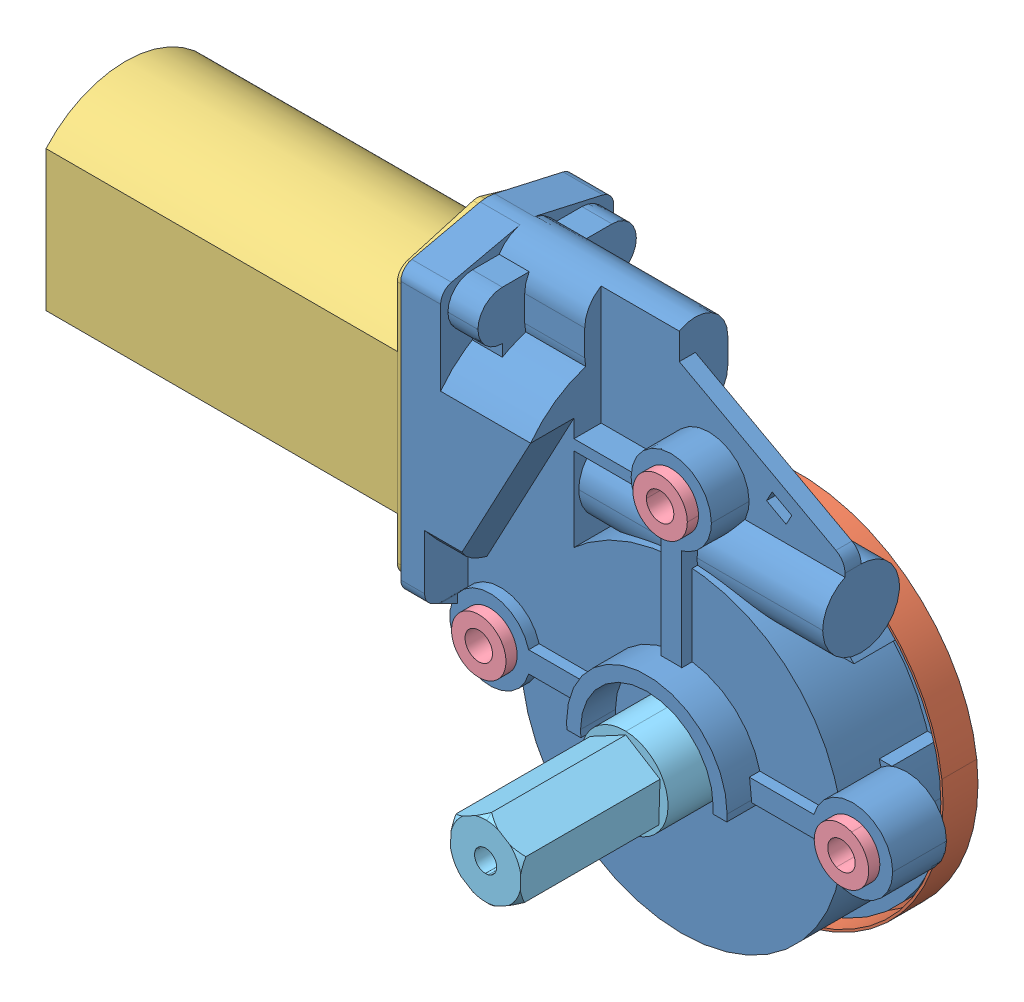
SolidWorks assembly am-2235a Snow Blower Motor With Hex Shaft, configuration Default. Lengths in mm.
Overall size (155.99 97.54 59.31).
8 component instances, 5 part files, 0 mates.
Components (placement in the parent):
- am-2235a Snow Blower Motor With Hex Shaft.STEP-1: am-2235a Snow Blower Motor With Hex Shaft.STEP [Default] at origin size (155.99 97.54 59.31)
  - AM-2235 gearbox housing.STEP-1: AM-2235 gearbox housing.STEP [Default] at (-23.1571 -13.8454 22.0708) size (83.55 92.74 31.5)
  - AM-2235 gear cap.STEP-1: AM-2235 gear cap.STEP [Default] at (-23.1571 -13.8454 -0.2812) x (0.99315 0.116843 0) z (0 0 1) size (65.41 65.41 6.35)
  - AM-2235 motor.STEP-1: AM-2235 motor.STEP [Default] at (-132.2374 16.5562 12.2918) x (0 0 1) z (-1 0 0) size (28.96 59.84 72.44)
  - AM-2235 threaded insert.STEP-1: AM-2235 threaded insert.STEP [Default] at (-56.1571 -12.3454 22.0708) x (-0.667171 0.744904 0) z (0 0 1) size (9.91 9.91 11.94)
  - AM-2235 threaded insert.STEP-2: AM-2235 threaded insert.STEP [Default] at (-23.1571 26.1447 22.0708) size (9.91 9.91 11.94)
  - AM-2235 threaded insert.STEP-3: AM-2235 threaded insert.STEP [Default] at (9.8429 -12.3454 22.0708) x (0.372744 0.927934 0) z (0 0 1) size (9.91 9.91 11.94)
  - AM-2235a hex output shaft.STEP-1: AM-2235a hex output shaft.STEP [Default] at (-23.1571 -13.8454 45.8198) x (-0.031978 -0.999489 0) z (0 0 1) size (15.85 15.85 35.69)
